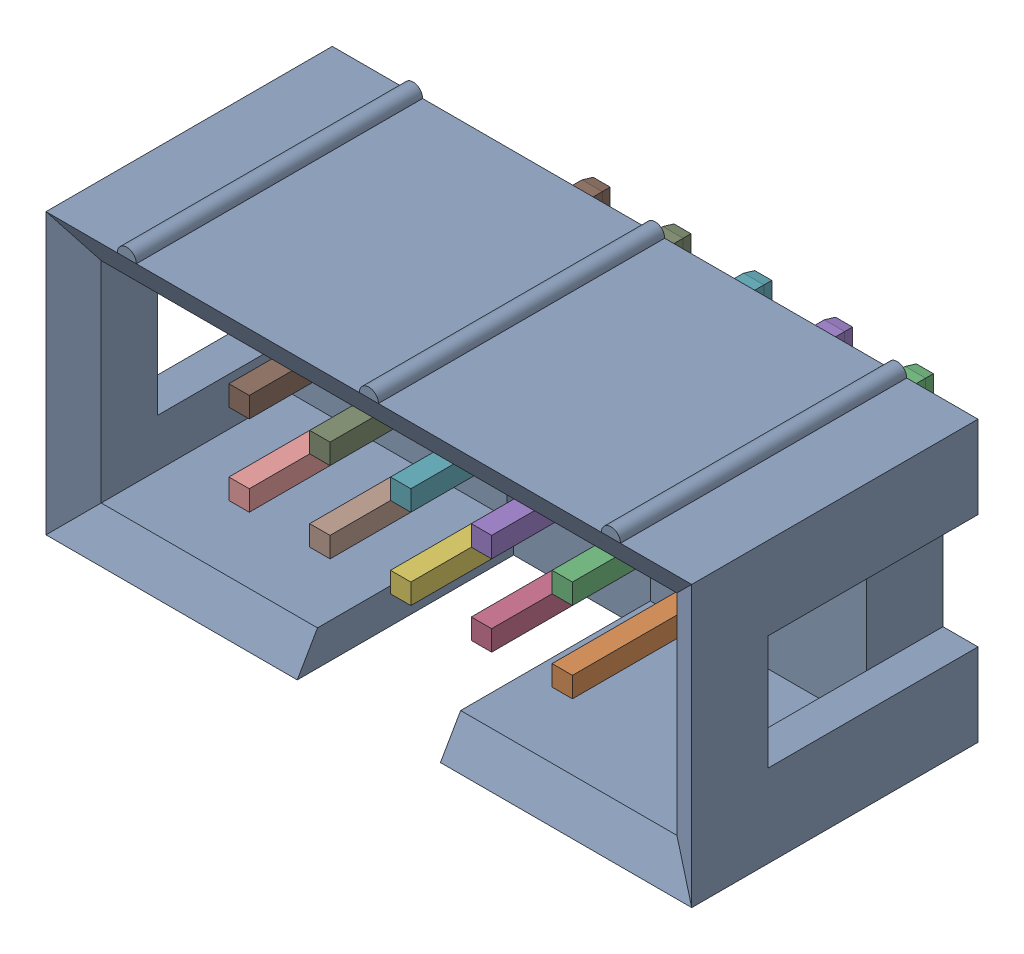
SolidWorks assembly IDC2X5P, configuration 默认. Lengths in mm.
Overall size (20.3 9.1 12.4).
12 component instances, 2 part files, 0 mates.
Components (placement in the parent):
- User Library-IDC-10M-1: User Library-IDC-10M [默认] at origin size (20.3 9.1 12.4)
  - IDC-10M_Body___ _________-1: IDC-10M_Body___ _________ [默认] at origin size (20.3 9.1 9.3)
  - IDC_pin___ _________-1: IDC_pin___ _________ [默认] at (5.08 -1.27 -3.1) size (0.64 0.64 11.4)
  - IDC_pin___ _________-2: IDC_pin___ _________ [默认] at (5.08 1.27 -3.1) size (0.64 0.64 11.4)
  - IDC_pin___ _________-3: IDC_pin___ _________ [默认] at (2.54 -1.27 -3.1) size (0.64 0.64 11.4)
  - IDC_pin___ _________-4: IDC_pin___ _________ [默认] at (2.54 1.27 -3.1) size (0.64 0.64 11.4)
  - IDC_pin___ _________-5: IDC_pin___ _________ [默认] at (0 -1.27 -3.1) size (0.64 0.64 11.4)
  - IDC_pin___ _________-6: IDC_pin___ _________ [默认] at (0 1.27 -3.1) size (0.64 0.64 11.4)
  - IDC_pin___ _________-7: IDC_pin___ _________ [默认] at (-2.54 -1.27 -3.1) size (0.64 0.64 11.4)
  - IDC_pin___ _________-8: IDC_pin___ _________ [默认] at (-2.54 1.27 -3.1) size (0.64 0.64 11.4)
  - IDC_pin___ _________-9: IDC_pin___ _________ [默认] at (-5.08 -1.27 -3.1) size (0.64 0.64 11.4)
  - IDC_pin___ _________-10: IDC_pin___ _________ [默认] at (-5.08 1.27 -3.1) size (0.64 0.64 11.4)
